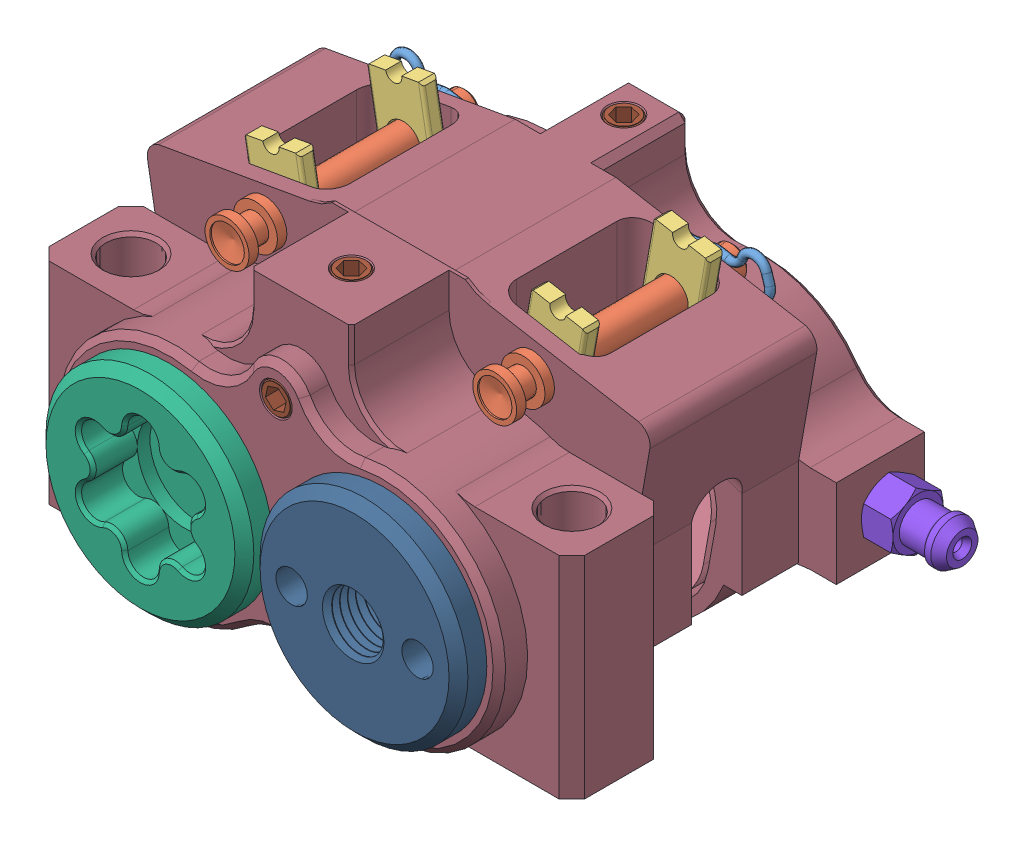
SolidWorks assembly PUTM-S-SR-BS-ISR 22-048-OB, configuration Domyślna. Lengths in mm.
Overall size (110 56.69 65.5).
37 component instances, 13 part files, 0 mates.
Components (placement in the parent):
- PUTM-S-SF-BS-waMygga_11-1: PUTM-S-SF-BS-waMygga_11 [Domyślna] at (-17.5609 -133.3811 -3) x (-1 0 0) z (0 1 0) size (17.93 1.25 6.8)
- PUTM-S-SF-BS-waKlosspinne_21-1: PUTM-S-SF-BS-waKlosspinne_21 [Domyślna] at (17.8101 -133.1311 -28) x (1 0 0) z (0 1 0) size (7 38 7)
- PUTM-S-SF-BS-waBromskloss_31-1: PUTM-S-SF-BS-waBromskloss_31 [Domyślna] at (18.7637 11.8437 8.4133) x (-0.996957 -0.077953 0) z (-0.077953 0.996957 0) size (31.91 7 47.71)
  - PUTM-S-SF-BS-waKlossplatta_301-1: PUTM-S-SF-BS-waKlossplatta_301 [Domyślna] at (35.6266 20.0867 -145.2058) size (31.91 2.5 47.71)
  - PUTM-S-SF-BS-waKlossbelgg_311-1: PUTM-S-SF-BS-waKlossbelgg_311 [Domyślna] at (35.6266 20.0867 -145.2058) size (30.8 4.5 27.94)
- PUTM-S-SF-BS-waKolv_41-1: PUTM-S-SF-BS-waKolv_41 [Domyślna] at (-117 -100 -24) size (25 25 13)
- PUTM-S-SF-BS-waLock upphjt_51-1: PUTM-S-SF-BS-waLock upphjt_51 [Domyślna] at (-17 0 24.5) size (34.64 33 13)
- PUTM-S-SF-BS-waKlosspinne_21-2: PUTM-S-SF-BS-waKlosspinne_21 [Domyślna] at (60.3061 -133.1311 -28) x (1 0 0) z (0 1 0) size (7 38 7)
- PUTM-S-SF-BS-waKula_71-1: PUTM-S-SF-BS-waKula_71 [Domyślna] at (-53.1899 32.9216 -130.9377) size (4 4 4)
- PUTM-S-SF-BS-waLuftnippel_81-1: PUTM-S-SF-BS-waLuftnippel_81 [Domyślna] at (-55 -100 -21) x (0 -1 0) z (1 0 0) size (9.24 8 25)
- PUTM-S-SF-BS-waKolv_41-2: PUTM-S-SF-BS-waKolv_41 [Domyślna] at (147.6777 -54.0679 24) x (-0.923728 -0.383049 0) z (0 0 -1) size (25 25 13)
- PUTM-S-SF-BS-waTtring_101-1: PUTM-S-SF-BS-waTtring_101 [Domyślna] at (-50 134 55.9989) x (1 0 0) z (0 -1 0) size (31 3 31)
- PUTM-S-SF-BS-waKolv_41-3: PUTM-S-SF-BS-waKolv_41 [Domyślna] at (-83 -100 -24) size (25 25 13)
- PUTM-S-SF-BS-waBromskloss_31-2: PUTM-S-SF-BS-waBromskloss_31 [Domyślna] at (-18.7637 11.8437 -8.4133) x (0.996957 -0.077953 0) z (0.077953 0.996957 0) size (31.91 7 47.71)
  - PUTM-S-SF-BS-waKlossplatta_301-1: PUTM-S-SF-BS-waKlossplatta_301 [Domyślna] at (35.6266 20.0867 -145.2058) size (31.91 2.5 47.71)
  - PUTM-S-SF-BS-waKlossbelgg_311-1: PUTM-S-SF-BS-waKlossbelgg_311 [Domyślna] at (35.6266 20.0867 -145.2058) size (30.8 4.5 27.94)
- PUTM-S-SF-BS-waLuftnippel_81-2: PUTM-S-SF-BS-waLuftnippel_81 [Domyślna] at (55 100 -21) x (0 1 0) z (-1 0 0) size (9.24 8 25)
- PUTM-S-SF-BS-waKolv_41-4: PUTM-S-SF-BS-waKolv_41 [Domyślna] at (113.6777 -54.0679 24) x (-0.923728 -0.383049 0) z (0 0 -1) size (25 25 13)
- PUTM-S-SF-BS-waTtring_101-2: PUTM-S-SF-BS-waTtring_101 [Domyślna] at (-16 -134 -56.9989) x (1 0 0) z (0 1 0) size (31 3 31)
- PUTM-S-SF-BS-waTtring_101-3: PUTM-S-SF-BS-waTtring_101 [Domyślna] at (-16 -134 -28.5011) x (1 0 0) z (0 1 0) size (31 3 31)
- PUTM-S-SF-BS-waLock m nippel_171-1: PUTM-S-SF-BS-waLock m nippel_171 [Domyślna] at (17 0 24.5) size (34.64 33 13)
- PUTM-S-SF-BS-waM6_plugg_181-1: PUTM-S-SF-BS-waM6_plugg_181 [Domyślna] at (11.0714 26.7893 -134.6783) x (0.916429 -0.086532 0.390731) z (-0.389001 0.036731 0.920505) size (7.48 6 7.28)
- PUTM-S-SF-BS-waBromskloss_31-3: PUTM-S-SF-BS-waBromskloss_31 [Domyślna] at (19.3288 11.7426 -8.4133) x (0.90799 -0.418991 0) z (0.418991 0.90799 0) size (31.91 7 47.71)
  - PUTM-S-SF-BS-waKlossplatta_301-1: PUTM-S-SF-BS-waKlossplatta_301 [Domyślna] at (35.6266 20.0867 -145.2058) size (31.91 2.5 47.71)
  - PUTM-S-SF-BS-waKlossbelgg_311-1: PUTM-S-SF-BS-waKlossbelgg_311 [Domyślna] at (35.6266 20.0867 -145.2058) size (30.8 4.5 27.94)
- PUTM-S-SF-BS-waMygga_11-2: PUTM-S-SF-BS-waMygga_11 [Domyślna] at (17.4279 -133.3811 -28) x (1 0 0) z (0 1 0) size (17.93 1.25 6.8)
- PUTM-S-SF-BS-waOring_evo2_211-1: PUTM-S-SF-BS-waOring_evo2_211 [Domyślna] at (-17 0 25.5) x (0 0 1) z (-1 0 0) size (1.5 30.5 30.5)
- PUTM-S-SF-BS-waTtring_101-4: PUTM-S-SF-BS-waTtring_101 [Domyślna] at (-50 -134 -56.9989) x (1 0 0) z (0 1 0) size (31 3 31)
- PUTM-S-SF-BS-waM6_plugg_181-2: PUTM-S-SF-BS-waM6_plugg_181 [Domyślna] at (6.511 -135.6783 9.7626) x (0.847329 0.390731 -0.35967) z (-0.35967 0.920505 0.152671) size (7.48 6 7.28)
- PUTM-S-SF-BS-ISR 22-048-OB_241-1: PUTM-S-SF-BS-ISR 22-048-OB_241 [Domyślna] at origin size (86 50.5 61.59)
- PUTM-S-SF-BS-waOring_evo2_211-2: PUTM-S-SF-BS-waOring_evo2_211 [Domyślna] at (17 0 25.5) x (0 0 -1) z (1 0 0) size (1.5 30.5 30.5)
- PUTM-S-SF-BS-waKula_71-2: PUTM-S-SF-BS-waKula_71 [Domyślna] at (-53.1216 27.777 -125.5264) size (4 4 4)
- PUTM-S-SF-BS-waM6_plugg_181-3: PUTM-S-SF-BS-waM6_plugg_181 [Domyślna] at (6.511 -136.1783 -33.4874) x (0.847329 0.390731 -0.35967) z (-0.35967 0.920505 0.152671) size (7.48 6 7.28)
- PUTM-S-SF-BS-waBromskloss_31-4: PUTM-S-SF-BS-waBromskloss_31 [Domyślna] at (-19.3288 11.7426 8.4133) x (-0.90799 -0.418991 0) z (-0.418991 0.90799 0) size (31.91 7 47.71)
  - PUTM-S-SF-BS-waKlossplatta_301-1: PUTM-S-SF-BS-waKlossplatta_301 [Domyślna] at (35.6266 20.0867 -145.2058) size (31.91 2.5 47.71)
  - PUTM-S-SF-BS-waKlossbelgg_311-1: PUTM-S-SF-BS-waKlossbelgg_311 [Domyślna] at (35.6266 20.0867 -145.2058) size (30.8 4.5 27.94)
- PUTM-S-SF-BS-waKula_71-3: PUTM-S-SF-BS-waKula_71 [Domyślna] at (-53.2674 32.5327 -174.1198) size (4 4 4)
